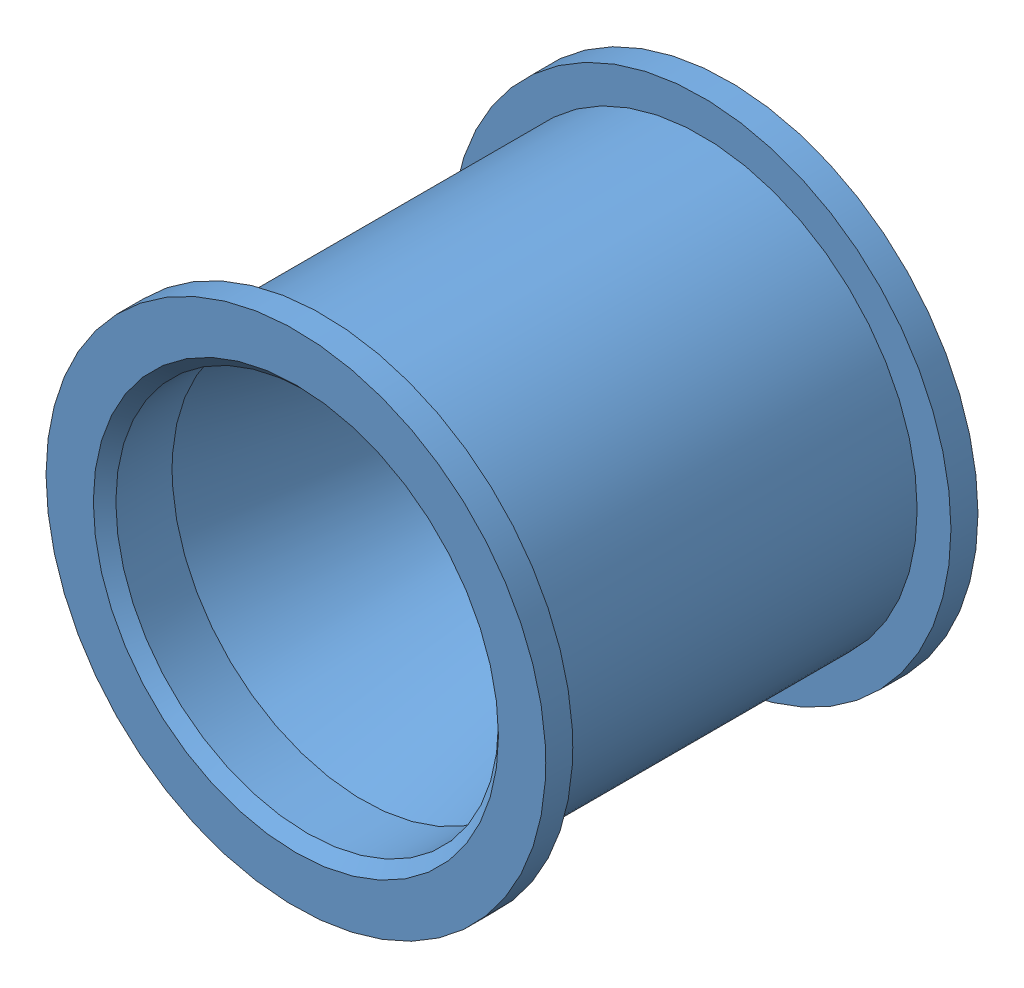
SolidWorks assembly bg_PipeMouse_Laufrad, configuration Standard. Lengths in mm.
Overall size (22.2 22.2 19.4).
4 component instances, 3 part files, 6 mates.
Components (placement in the parent):
- pipemouse_KettenRad_v3-2: pipemouse_KettenRad_v3 [Standard] at (-2.0342 0.2506 22.2) size (22.2 22.2 19.2)
- pipemouse_Kugellager_8x3x4-1: pipemouse_Kugellager_8x3x4 [Standard] at (-2.0342 0.2506 12.6) x (0.986697 0.162571 0) z (0 0 1) size (8 8 4)
- pipemouse_U-Scheibe-1: pipemouse_U-Scheibe [Standard] at (-2.0342 0.2506 12.6) x (1 0 0) z (0 1 0) size (6.4 0.2 6.4)
- pipemouse_U-Scheibe-2: pipemouse_U-Scheibe [Standard] at (-2.0342 0.2506 19.6) x (-0.923728 -0.383049 0) z (-0.383049 0.923728 0) size (6.4 0.2 6.4)
Mates (geometry in assembly coordinates):
- Konzentrisch1: concentric aligned: cylinder of pipemouse_KettenRad_v3-2 through (-2.0342 0.2506 16.6) axis (0 0 -1) radius 4.1; cylinder of pipemouse_Kugellager_8x3x4-1 through (-2.0342 0.2506 16.6) axis (0 0 -1) radius 4
- Deckungsgleich1: coincident anti-aligned: plane of pipemouse_KettenRad_v3-2 through (-2.0342 0.2506 16.6) normal (0 0 -1); plane of pipemouse_Kugellager_8x3x4-1 through (-2.0342 0.2506 16.6) normal (0 0 1)
- Deckungsgleich2: coincident anti-aligned: plane of pipemouse_Kugellager_8x3x4-1 through (-2.0342 0.2506 12.6) normal (0 0 -1); plane of pipemouse_U-Scheibe-1 through (-0.4342 0.2506 12.6) normal (0 0 1)
- Konzentrisch2: concentric anti-aligned: cylinder of pipemouse_Kugellager_8x3x4-1 through (-2.0342 0.2506 16.6) axis (0 0 -1) radius 1.5; cylinder of pipemouse_U-Scheibe-1 through (-2.0342 0.2506 12.6) axis (0 0 1) radius 1.6
- Deckungsgleich3: coincident anti-aligned: plane of pipemouse_KettenRad_v3-2 through (-2.0342 6.2506 19.6) normal (0 0 1); plane of pipemouse_U-Scheibe-2 through (-3.5122 -0.3623 19.6) normal (0 0 -1)
- Konzentrisch3: concentric aligned: cylinder of pipemouse_KettenRad_v3-2 through (-2.0342 0.2506 31.8) axis (0 0 -1) radius 1.65; cylinder of pipemouse_U-Scheibe-2 through (-2.0342 0.2506 19.6) axis (0 0 -1) radius 1.6
